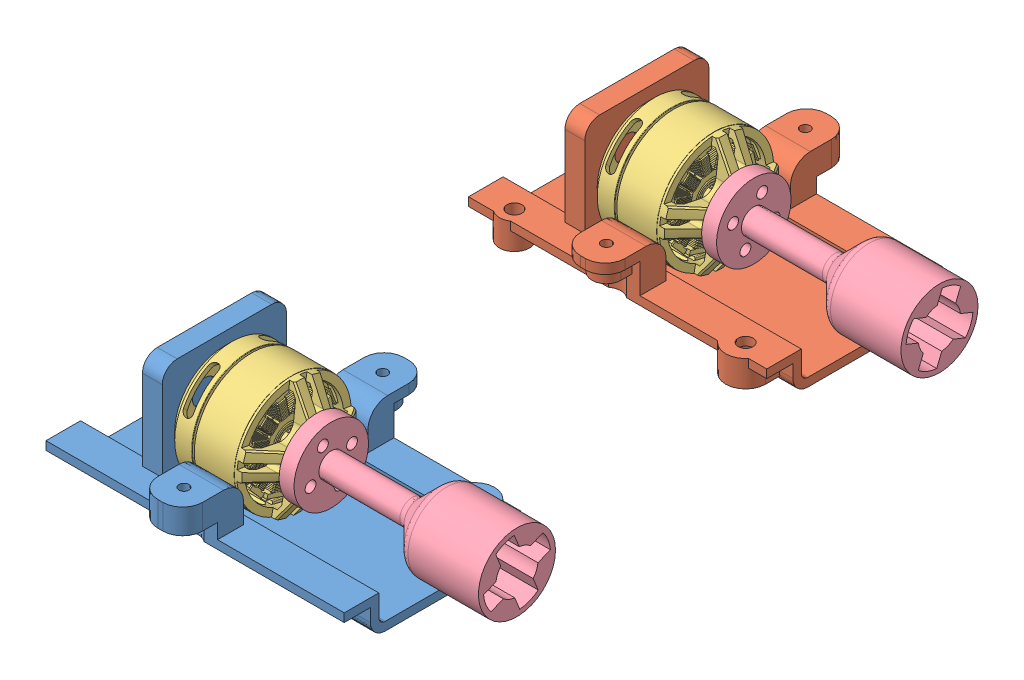
SolidWorks assembly Speedboat Motor assembly, configuration Default. Lengths in mm.
Overall size (77 32.67 134.5).
6 component instances, 4 part files, 10 mates.
Components (placement in the parent):
- Motormount Left-1: Motormount Left [Default] at (0 0 42.5) size (60 26.5 49.5)
- Motormount LeftRight-2: Motormount LeftRight [Default] at (0 0 -42.5) size (60 26.5 49.5)
- DYS BE 1806 complet-1: DYS BE 1806 complet [Défaut] at (-11.8598 6.7 42.5) x (0 0.707107 0.707107) z (0 0.707107 -0.707107) size (23.1 22.15 23.1)
- DYS BE 1806 complet-2: DYS BE 1806 complet [Défaut] at (-11.8598 6.7 -42.5) x (0 0.707107 -0.707107) z (0 -0.707107 -0.707107) size (23.1 22.15 23.1)
- Motoraxis-1: Motoraxis [Default] at (36 6.7 42.5) x (1 0 0) z (0 -0.927266 -0.374404) size (40.36 15.5 15.5)
- Motoraxis-2: Motoraxis [Default] at (36 6.7 -42.5) x (1 0 0) z (0 0.927266 -0.374404) size (40.36 15.5 15.5)
Mates (geometry in assembly coordinates):
- Coincident1: coincident aligned: plane of Motormount Left-1 through (0 0 42.5) normal (0 1 0); plane of assembly through (0 0 0) normal (0 1 0)
- Coincident2: coincident aligned: plane of Motormount Left-1 through (0 0 42.5) normal (1 0 0); plane of assembly through (0 0 0) normal (1 0 0)
- Coincident3: coincident aligned: plane of Motormount Left-1 through (0 0 42.5) normal (0 0 1); plane of assembly through (0 0 42.5) normal (0 0 1)
- Concentric1: concentric anti-aligned: cylinder of Motormount Left-1 through (-30 6.7 34.5) axis (1 0 0) radius 1.55; cylinder of DYS BE 1806 complet-1 through (-11.8598 6.7 34.5) axis (-1 0 0) radius 0.8
- Concentric2: concentric anti-aligned: cylinder of Motormount Left-1 through (-30 12.7 42.5) axis (1 0 0) radius 1.55; cylinder of DYS BE 1806 complet-1 through (-11.8598 12.7 42.5) axis (-1 0 0) radius 0.8
- Concentric3: concentric: cylinder of DYS BE 1806 complet-1 through (6.6402 5.9625 45.5609) axis (1 0 0) radius 0.8; cylinder of Motoraxis-1 through (96.5546 5.9625 45.5609) axis (-1 0 0) radius 1.1
- Concentric4: concentric anti-aligned: cylinder of DYS BE 1806 complet-1 through (6.6402 11.1391 49.2625) axis (1 0 0) radius 0.8; cylinder of Motoraxis-1 through (81.6283 11.1391 49.2625) axis (-1 0 0) radius 1.1
- Coincident4: coincident anti-aligned: plane of Motormount Left-1 through (-11.8598 -5.3 55) normal (1 0 0); plane of DYS BE 1806 complet-1 through (-11.8598 6.7 42.5) normal (-1 0 0)
- Coincident5: coincident anti-aligned: plane of DYS BE 1806 complet-1 through (6.6402 7.7653 48.9121) normal (1 0 0); plane of Motoraxis-1 through (6.6402 3.892 49.4545) normal (-1 0 0)
- Concentric5: concentric anti-aligned: cylinder of DYS BE 1806 complet-1 through (9.6402 6.7 42.5) axis (-1 0 0) radius 1; cylinder of Motoraxis-1 through (6.6402 6.7 42.5) axis (1 0 0) radius 1.1
